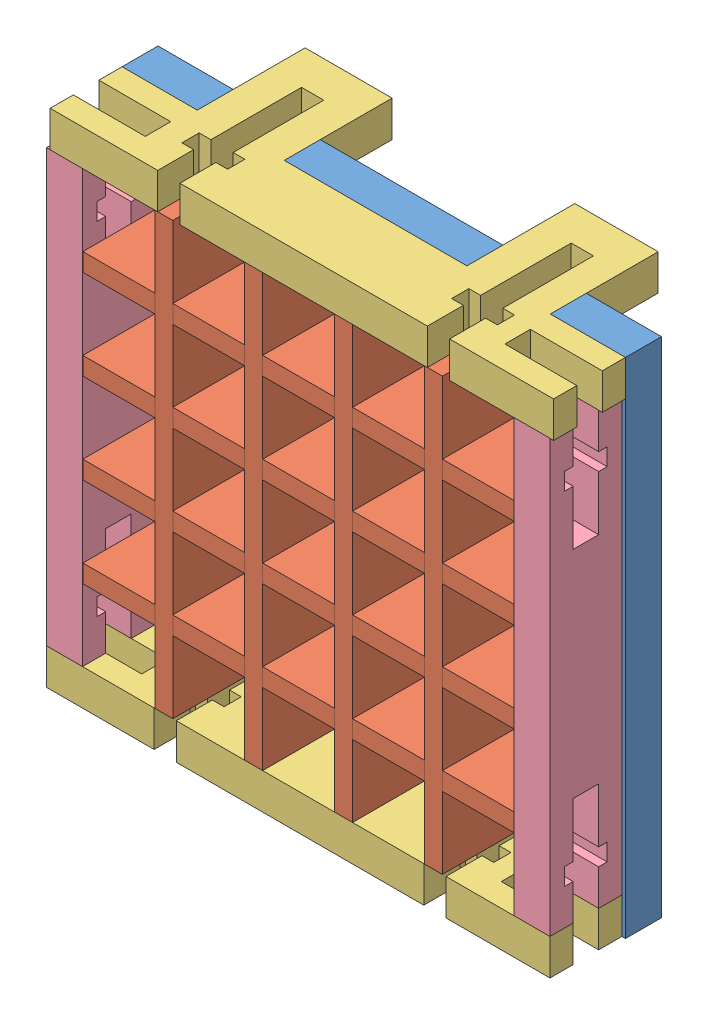
SolidWorks assembly grid_box_5_5, configuration Default. Lengths in mm.
Overall size (89.54 88.88 31.75).
14 component instances, 4 part files, 13 mates.
Components (placement in the parent):
- gridbox_baseplate_5x5_1cm_1_8-1: gridbox_baseplate_5x5_1cm_1_8 [Default] at (58.2118 9.8338 79.7956) x (-1 0 0) z (0 1 0) size (88.9 6.35 88.88)
- grid_wall_5_5-2: grid_wall_5_5 [Default] at (-5.9207 24.5202 25.0602) size (76.2 76.2 12.7)
  - divider_wall_5_0_5_0_5-1: divider_wall_5_0_5_0_5 [Default] at (-18.9925 51.9886 61.0854) size (76.2 3.17 12.7)
  - divider_wall_5_0_5_0_5-4: divider_wall_5_0_5_0_5 [Default] at (41.3325 -8.3364 73.7854) x (0 1 0) z (0 0 -1) size (76.2 3.17 12.7)
  - divider_wall_5_0_5_0_5-5: divider_wall_5_0_5_0_5 [Default] at (-18.9925 36.1136 61.0854) size (76.2 3.17 12.7)
  - divider_wall_5_0_5_0_5-6: divider_wall_5_0_5_0_5 [Default] at (-18.9925 20.2386 61.0854) size (76.2 3.17 12.7)
  - divider_wall_5_0_5_0_5-7: divider_wall_5_0_5_0_5 [Default] at (-18.9925 4.3636 61.0854) size (76.2 3.17 12.7)
  - divider_wall_5_0_5_0_5-8: divider_wall_5_0_5_0_5 [Default] at (-3.1175 67.8636 73.7854) x (0 -1 0) z (0 0 -1) size (76.2 3.17 12.7)
  - divider_wall_5_0_5_0_5-9: divider_wall_5_0_5_0_5 [Default] at (12.7575 67.8636 73.7854) x (0 -1 0) z (0 0 -1) size (76.2 3.17 12.7)
  - divider_wall_5_0_5_0_5-10: divider_wall_5_0_5_0_5 [Default] at (28.6325 67.8636 73.7854) x (0 -1 0) z (0 0 -1) size (76.2 3.17 12.7)
- grid_box_5_5_side_wall_bot_tabs-1: grid_box_5_5_side_wall_bot_tabs [Default] at (-30.6882 92.3603 86.1456) size (88.9 6.35 31.75)
- grid_box_5_5_side_wall_bot_tabs-2: grid_box_5_5_side_wall_bot_tabs [Default] at (-31.3248 9.8338 86.1456) size (88.9 6.35 31.75)
- grid_box_5_5_side_wall-1: grid_box_5_5_side_wall [Default] at (51.2252 92.3838 86.1456) x (0 -1 0) z (0 0 1) size (76.2 6.35 12.7)
- grid_box_5_5_side_wall-2: grid_box_5_5_side_wall [Default] at (-31.3248 92.3838 86.1456) x (0 -1 0) z (0 0 1) size (76.2 6.35 12.7)
Mates (geometry in assembly coordinates):
- Coincident4: coincident aligned: line of gridbox_baseplate_5x5_1cm_1_8-1 through (51.8618 79.6838 86.1456) axis (-1 0 0); line of grid_wall_5_5-2/divider_wall_5_0_5_0_5-1 through (51.2868 79.6838 86.1456) axis (-1 0 0)
- Coincident5: coincident anti-aligned: line of gridbox_baseplate_5x5_1cm_1_8-1 through (-12.2132 16.1838 86.1456) axis (0 1 0); line of grid_wall_5_5-2/divider_wall_5_0_5_0_5-8 through (-12.2132 76.5088 86.1456) axis (0 -1 0)
- Coincident6: coincident aligned: plane of gridbox_baseplate_5x5_1cm_1_8-1 through (-30.6882 9.8338 79.7956) normal (-1 0 0); plane of grid_box_5_5_side_wall_bot_tabs-1 through (-30.6882 98.7103 86.1456) normal (-1 0 0)
- Coincident7: coincident anti-aligned: plane of gridbox_baseplate_5x5_1cm_1_8-1 through (58.2118 9.8338 86.1456) normal (0 0 1); plane of grid_box_5_5_side_wall_bot_tabs-1 through (-30.6882 98.7103 86.1456) normal (0 0 -1)
- Coincident8: coincident aligned: plane of gridbox_baseplate_5x5_1cm_1_8-1 through (58.2118 98.7103 79.7956) normal (0 1 0); plane of grid_box_5_5_side_wall_bot_tabs-1 through (-30.6882 98.7103 86.1456) normal (0 1 0)
- Coincident9: coincident anti-aligned: plane of gridbox_baseplate_5x5_1cm_1_8-1 through (58.2118 9.8338 86.1456) normal (0 0 1); plane of grid_box_5_5_side_wall_bot_tabs-2 through (-31.3248 16.1838 86.1456) normal (0 0 -1)
- Coincident10: coincident anti-aligned: plane of gridbox_baseplate_5x5_1cm_1_8-1 through (-2.6882 16.1838 79.7956) normal (-1 0 0); plane of grid_box_5_5_side_wall_bot_tabs-2 through (-2.6882 9.8338 67.0956) normal (1 0 0)
- Coincident11: coincident anti-aligned: plane of gridbox_baseplate_5x5_1cm_1_8-1 through (-7.8007 16.1838 79.7956) normal (0 -1 0); plane of grid_box_5_5_side_wall_bot_tabs-2 through (-31.3248 16.1838 86.1456) normal (0 1 0)
- Coincident12: coincident anti-aligned: plane of grid_box_5_5_side_wall_bot_tabs-2 through (-31.3248 16.1838 86.1456) normal (0 1 0); plane of grid_box_5_5_side_wall-1 through (57.5752 16.1838 86.1456) normal (0 -1 0)
- Coincident13: coincident anti-aligned: plane of gridbox_baseplate_5x5_1cm_1_8-1 through (58.2118 9.8338 86.1456) normal (0 0 1); plane of grid_box_5_5_side_wall-1 through (57.5752 92.3838 86.1456) normal (0 0 -1)
- Coincident14: coincident aligned: plane of grid_box_5_5_side_wall_bot_tabs-2 through (57.5752 16.1838 86.1456) normal (1 0 0); plane of grid_box_5_5_side_wall-1 through (57.5752 92.3838 86.1456) normal (1 0 0)
- Coincident15: coincident anti-aligned: plane of grid_box_5_5_side_wall_bot_tabs-2 through (-31.3248 16.1838 86.1456) normal (0 1 0); plane of grid_box_5_5_side_wall-2 through (-24.9748 16.1838 86.1456) normal (0 -1 0)
- Coincident17: coincident aligned: plane of grid_box_5_5_side_wall_bot_tabs-2 through (-31.3248 16.1838 86.1456) normal (-1 0 0); plane of grid_box_5_5_side_wall-2 through (-31.3248 92.3838 86.1456) normal (-1 0 0)
